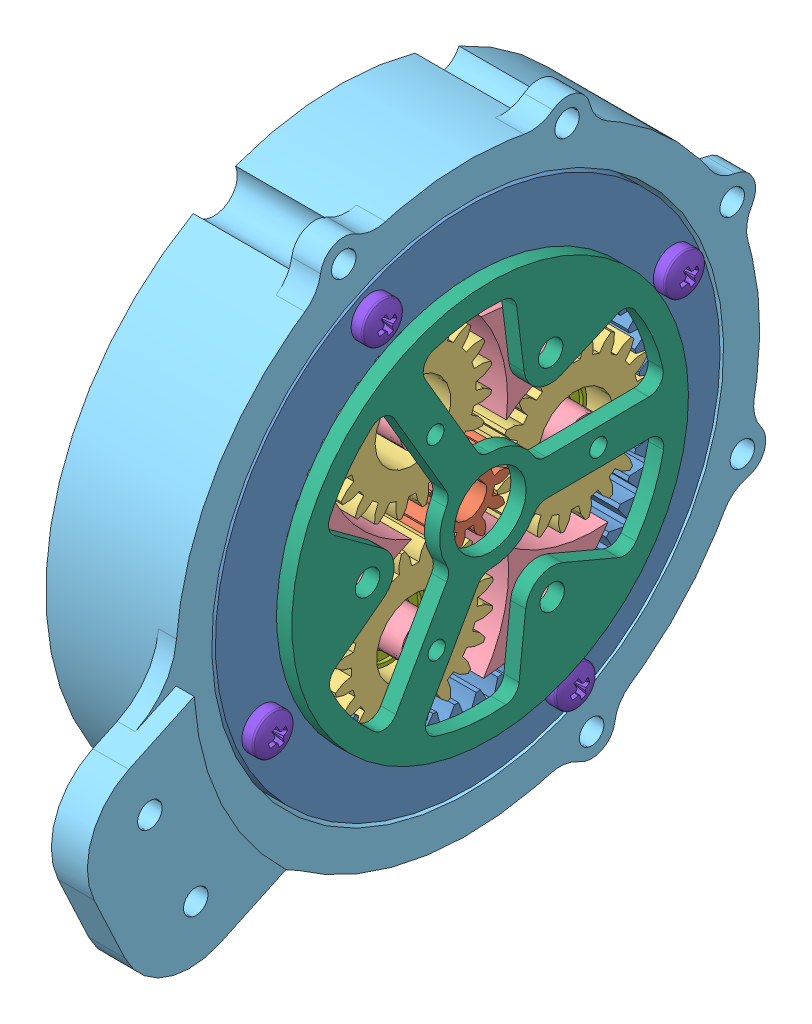
SolidWorks assembly ReductorDeRodillaEsnamble, configuration Predeterminado. Lengths in mm.
Overall size (23.11 122.25 128.92).
14 component instances, 8 part files, 59 mates.
Components (placement in the parent):
- internal spur gear_iso-15: internal spur gear_iso [ISO - Internal spur gear 1M 50T 20PA 10FW ---S50S70OD 1.0AF] at (25.094 2.7735 0) x (1 0 0) z (0 0.905496 0.424354) size (10 70 70)
- sol-2: sol [ISO - Spur gear 1M 10T 20PA 10FW ---S10A75H50L0.8N] at (25.094 2.7735 0) x (1 0 0) z (0 -0.637244 0.770662) size (20 11.48 12)
- Planeta-20: Planeta [ISO - Spur gear 1M 20T 20PA 10FW ---S20A75H50L0.8N] at (25.094 -10.2716 7.4045) x (1 0 0) z (0 -0.292495 0.956267) size (10 21.8 21.8)
- Planeta-18: Planeta [ISO - Spur gear 1M 20T 20PA 10FW ---S20A75H50L0.8N] at (25.094 2.8835 -14.9996) x (1 0 0) z (0 0.577293 -0.816537) size (10 21.8 21.8)
- Planeta-19: Planeta [ISO - Spur gear 1M 20T 20PA 10FW ---S20A75H50L0.8N] at (25.094 15.7085 7.5951) x (1 0 0) z (0 0.299258 -0.954172) size (10 21.8 21.8)
- PortaPlanetas-1: PortaPlanetas [Predeterminado] at (19.594 2.7735 0) x (0 0.493632 0.869671) z (0 0.869671 -0.493632) size (50.52 16.5 49.09)
- CampanaDeRodilla-1: CampanaDeRodilla [Predeterminado] at (26.094 2.7735 0) x (0 -0.905496 -0.424354) z (0 -0.424354 0.905496) size (87.5 20.5 101.37)
- TapaDeportaPlanetasReductorR-1: TapaDeportaPlanetasReductorR [Predeterminado] at (38.204 2.7735 0) x (0 0.999973 0.007338) z (0 -0.007338 0.999973) size (55 2.11 55)
- Rodamiento-2: Rodamiento [Predeterminado] at (31.594 2.8835 -14.9996) x (0 -0.461663 0.887055) z (0 -0.887055 -0.461663) size (10 3 10)
- Rodamiento-3: Rodamiento [Predeterminado] at (31.594 -10.2716 7.4045) x (0 0.729092 0.684416) z (0 -0.684416 0.729092) size (10 3 10)
- pan head cross recess screw_iso-10: pan head cross recess screw_iso [ISO 7045 - M3 x 20 - Z - 20N] at (37.494 31.2966 13.3671) x (-1 0 0) z (0 0.924225 0.381849) size (22.35 5.6 5.6)
- pan head cross recess screw_iso-11: pan head cross recess screw_iso [ISO 7045 - M3 x 20 - Z - 20N] at (37.494 -25.7497 -13.3671) x (-1 0 0) z (0 0.924225 0.381849) size (22.35 5.6 5.6)
- pan head cross recess screw_iso-12: pan head cross recess screw_iso [ISO 7045 - M3 x 20 - Z - 20N] at (37.494 16.1406 -28.5231) x (-1 0 0) z (0 -0.924225 -0.381849) size (22.35 5.6 5.6)
- pan head cross recess screw_iso-13: pan head cross recess screw_iso [ISO 7045 - M3 x 20 - Z - 20N] at (37.494 -10.5937 28.5231) x (-1 0 0) z (0 -0.924225 -0.381849) size (22.35 5.6 5.6)
Mates (geometry in assembly coordinates):
- Concéntrica1: concentric: circle of assembly; circle of assembly; circle of internal spur gear_iso-15; circle of PortaPlanetas-1
- Concéntrica2: concentric: circle of assembly; circle of Planeta-19; circle of PortaPlanetas-1
- Concéntrica3: concentric: circle of assembly; circle of Planeta-20; circle of PortaPlanetas-1
- Concéntrica4: concentric: circle of assembly; circle of Planeta-18; circle of PortaPlanetas-1
- Concéntrica5: concentric: circle of assembly; circle of PortaPlanetas-1; circle of sol-2
- Coincidente1: coincident: plane of assembly; plane of assembly; plane of internal spur gear_iso-15 through (35.094 -18.9584 -10.1845) normal (1 0 0); plane of Planeta-19 through (35.094 15.7085 7.5951) normal (1 0 0)
- Coincidente2: coincident: plane of assembly; plane of assembly; plane of internal spur gear_iso-15 through (35.094 -18.9584 -10.1845) normal (1 0 0); plane of Planeta-18 through (35.094 2.8835 -14.9996) normal (1 0 0)
- Coincidente3: coincident: plane of assembly; plane of assembly; plane of internal spur gear_iso-15 through (35.094 -18.9584 -10.1845) normal (1 0 0); plane of Planeta-20 through (35.094 -10.2716 7.4045) normal (1 0 0)
- Coincidente4: coincident: plane of assembly; plane of assembly; plane of internal spur gear_iso-15 through (35.094 -18.9584 -10.1845) normal (1 0 0); plane of sol-2 through (35.094 2.7735 0) normal (1 0 0)
- Relación de posición de engranaje2: gear = 10 : 20 mm: cylinder of Planeta-20 through (17.094 -10.2716 7.4045) axis (-1 0 0) radius 11; cylinder of sol-2 through (17.094 2.7735 0) axis (-1 0 0) radius 6
- Relación de posición de engranaje8: gear = 10 : 20 mm: cylinder of Planeta-19 through (17.094 15.7085 7.5951) axis (-1 0 0) radius 11; cylinder of sol-2 through (17.094 2.7735 0) axis (-1 0 0) radius 6
- Relación de posición de engranaje9: gear = 50 : 20 mm: cylinder of Planeta-19 through (17.094 15.7085 7.5951) axis (-1 0 0) radius 11; cylinder of internal spur gear_iso-15 through (15.094 2.7735 0) axis (-1 0 0) radius 24
- Distancia1: distance = 1 mm: plane of assembly; plane of assembly; plane of PortaPlanetas-1 through (24.094 2.7735 0) normal (1 0 0); plane of internal spur gear_iso-15 through (25.094 -18.9584 -10.1845) normal (-1 0 0)
- Concéntrica7: concentric: circle of PortaPlanetas-1; circle of TapaDeportaPlanetasReductorR-1
- Coincidente6: coincident: plane of assembly; plane of assembly; plane of PortaPlanetas-1 through (36.094 2.8835 -14.9996) normal (1 0 0); plane of TapaDeportaPlanetasReductorR-1 through (36.094 2.7735 0) normal (-1 0 0)
- Concéntrica8: concentric: circle of PortaPlanetas-1; circle of TapaDeportaPlanetasReductorR-1
- Concéntrica11: concentric: cylinder of CampanaDeRodilla-1 through (25.094 -10.5937 28.5231) axis (-1 0 0) radius 1.7; cylinder of ? through (68.394 17.9897 -27.5811) axis (1 0 0) radius 2.8
- Coincidente9: coincident: plane of CampanaDeRodilla-1 through (25.094 2.7735 0) normal (1 0 0); plane of ? through (40.594 17.4169 -26.1948) normal (-1 0 0)
- Concéntrica12: concentric: cylinder of ? through (68.394 17.9897 -27.5811) axis (1 0 0) radius 1.5; cylinder of ? through (0.7428 17.9897 -27.5811) axis (1 0 0) radius 1.5
- Concéntrica16: concentric: point of ?; cylinder of ? through (-3.606 13.4432 29.6379) axis (-1 0 0) radius 2.8
- Coincidente11: coincident: plane of internal spur gear_iso-15 through (25.094 -18.9584 -10.1845) normal (-1 0 0); plane of ? through (24.194 14.9432 29.6379) normal (1 0 0)
- Concéntrica17: concentric: cylinder of CampanaDeRodilla-1 through (25.094 -10.5937 28.5231) axis (-1 0 0) radius 1.7; cylinder of ? through (15.9565 13.4432 29.6379) axis (1 0 0) radius 1.5
- Coincidente12: coincident: plane of CampanaDeRodilla-1 through (25.094 2.7735 0) normal (1 0 0); plane of ? through (39.194 12.2307 32.5727) normal (-1 0 0)
- Concéntrica18: concentric: cylinder of CampanaDeRodilla-1 through (25.094 -25.7497 -13.3671) axis (-1 0 0) radius 1.7; cylinder of ? through (15.9565 -28.2286 -5.5787) axis (1 0 0) radius 1.5
- Coincidente13: coincident: plane of CampanaDeRodilla-1 through (25.094 2.7735 0) normal (1 0 0); plane of ? through (39.194 -31.404 -5.5787) normal (-1 0 0)
- Concéntrica19: concentric: cylinder of CampanaDeRodilla-1 through (25.094 16.1406 -28.5231) axis (-1 0 0) radius 1.7; cylinder of ? through (15.9565 23.1058 -24.0592) axis (1 0 0) radius 1.5
- Coincidente14: coincident: plane of CampanaDeRodilla-1 through (25.094 2.7735 0) normal (1 0 0); plane of ? through (39.194 26.2713 -23.8086) normal (-1 0 0)
- Concéntrica20: concentric: cylinder of internal spur gear_iso-15 through (39.0023 -28.2286 -5.5787) axis (-1 0 0) radius 1.7; cylinder of ? through (-3.606 -28.2286 -5.5787) axis (-1 0 0) radius 2.8
- Coincidente15: coincident: plane of internal spur gear_iso-15 through (25.094 -18.9584 -10.1845) normal (-1 0 0); plane of ? through (24.194 -26.7286 -5.5787) normal (1 0 0)
- Concéntrica21: concentric: cylinder of internal spur gear_iso-15 through (39.0023 23.1058 -24.0592) axis (-1 0 0) radius 1.7; cylinder of ? through (-3.606 23.1058 -24.0592) axis (-1 0 0) radius 2.8
- Coincidente16: coincident: plane of internal spur gear_iso-15 through (25.094 -18.9584 -10.1845) normal (-1 0 0); plane of ? through (24.194 24.6058 -24.0593) normal (1 0 0)
- Concéntrica23: concentric: cylinder of ? through (36.094 2.0107 -14.9806) axis (1 0 0) radius 1.2; cylinder of ? through (-5.206 -3.2103 13.7548) axis (-1 0 0) radius 2
- Coincidente18: coincident: plane of ? through (21.794 2.0107 -14.9806) normal (-1 0 0); plane of ? through (21.794 -2.2103 13.7548) normal (1 0 0)
- Concéntrica24: concentric: cylinder of ? through (36.094 16.1285 6.8297) axis (1 0 0) radius 1.2; cylinder of ? through (-5.206 -6.1466 -12.0595) axis (-1 0 0) radius 2
- Coincidente19: coincident: plane of ? through (21.794 16.1285 6.8297) normal (-1 0 0); plane of ? through (21.794 -7.0918 -11.733) normal (1 0 0)
- Concéntrica25: concentric: cylinder of ? through (36.094 -9.8187 8.1509) axis (1 0 0) radius 1.2; cylinder of ? through (-5.206 17.6774 -1.6953) axis (-1 0 0) radius 2
- Coincidente20: coincident: plane of ? through (21.794 -9.8187 8.1509) normal (-1 0 0); plane of ? through (21.794 16.6774 -1.6953) normal (1 0 0)
- Concéntrica27: concentric: unknown of PortaPlanetas-1; unknown of ?
- Ancho2: width: plane of ? through (29.094 -6.1466 -12.0595) normal (-1 0 0); plane of ? through (31.094 -6.1466 -12.0595) normal (1 0 0); plane of ? through (35.094 16.1285 6.8297) normal (1 0 0); plane of ? through (25.094 16.1285 6.8297) normal (-1 0 0)
- Concéntrica28: concentric: circle of assembly; circle of Planeta-20; circle of Rodamiento-3
- Concéntrica29: concentric: circle of assembly; circle of assembly; circle of PortaPlanetas-1; circle of Rodamiento-2
- Ancho3: width: plane of assembly; plane of assembly; plane of assembly; plane of assembly; plane of Rodamiento-2 through (31.094 2.8835 -14.9996) normal (1 0 0); plane of Rodamiento-2 through (29.094 2.8835 -14.9996) normal (-1 0 0); plane of Planeta-18 through (35.094 2.8835 -14.9996) normal (1 0 0); plane of Planeta-18 through (25.094 2.8835 -14.9996) normal (-1 0 0)
- Ancho4: width: plane of assembly; plane of assembly; plane of assembly; plane of assembly; plane of Rodamiento-3 through (31.094 -10.2716 7.4045) normal (1 0 0); plane of Rodamiento-3 through (29.094 -10.2716 7.4045) normal (-1 0 0); plane of Planeta-19 through (35.094 15.7085 7.5951) normal (1 0 0); plane of Planeta-19 through (25.094 15.7085 7.5951) normal (-1 0 0)
- Relación de posición de engranaje10: gear = 20 : 10 mm: cylinder of sol-2 through (17.094 2.7735 0) axis (-1 0 0) radius 6; cylinder of Planeta-18 through (17.094 2.8835 -14.9996) axis (-1 0 0) radius 11
- Concéntrica30: concentric: unknown of ?; unknown of PortaPlanetas-1
- Concéntrica31: concentric: circle of ?; circle of ?
- Concéntrica36: concentric: circle of PortaPlanetas-1; circle of ?
- Concéntrica37: concentric: circle of ?; circle of ?
- Coincidente21: coincident: plane of assembly; plane of assembly; plane of internal spur gear_iso-15 through (25.094 -18.9584 -10.1845) normal (-1 0 0); plane of CampanaDeRodilla-1 through (25.094 2.7735 0) normal (1 0 0)
- Concéntrica38: concentric: circle of assembly; circle of assembly; circle of CampanaDeRodilla-1; circle of TapaDeportaPlanetasReductorR-1
- Concéntrica39: concentric: circle of assembly; circle of internal spur gear_iso-15; circle of CampanaDeRodilla-1
- Concéntrica40: concentric: cylinder of assembly; cylinder of internal spur gear_iso-15 through (39.9023 31.2966 13.3671) axis (-1 0 0) radius 1.7; cylinder of pan head cross recess screw_iso-10 through (62.894 31.2966 13.3671) axis (1 0 0) radius 2.8
- Coincidente22: coincident: plane of internal spur gear_iso-15 through (35.094 -18.9584 -10.1845) normal (1 0 0); plane of pan head cross recess screw_iso-10 through (35.094 30.7238 14.7535) normal (-1 0 0)
- Concéntrica41: concentric: cylinder of assembly; cylinder of internal spur gear_iso-15 through (39.9023 -25.7497 -13.3671) axis (-1 0 0) radius 1.7; cylinder of pan head cross recess screw_iso-11 through (62.894 -25.7497 -13.3671) axis (1 0 0) radius 2.8
- Coincidente23: coincident: plane of internal spur gear_iso-15 through (35.094 -18.9584 -10.1845) normal (1 0 0); plane of pan head cross recess screw_iso-11 through (35.094 -26.3224 -11.9808) normal (-1 0 0)
- Concéntrica42: concentric: cylinder of assembly; cylinder of pan head cross recess screw_iso-12 through (62.894 16.1406 -28.5231) axis (1 0 0) radius 2.8; circle of internal spur gear_iso-15
- Coincidente24: coincident: plane of assembly; plane of assembly; plane of internal spur gear_iso-15 through (35.094 -18.9584 -10.1845) normal (1 0 0); plane of pan head cross recess screw_iso-12 through (35.094 16.7134 -29.9095) normal (-1 0 0)
- Concéntrica43: concentric: cylinder of assembly; cylinder of pan head cross recess screw_iso-13 through (62.894 -10.5937 28.5231) axis (1 0 0) radius 2.8; circle of internal spur gear_iso-15
- Coincidente25: coincident: plane of assembly; plane of assembly; plane of internal spur gear_iso-15 through (35.094 -18.9584 -10.1845) normal (1 0 0); plane of pan head cross recess screw_iso-13 through (35.094 -10.0209 27.1368) normal (-1 0 0)
